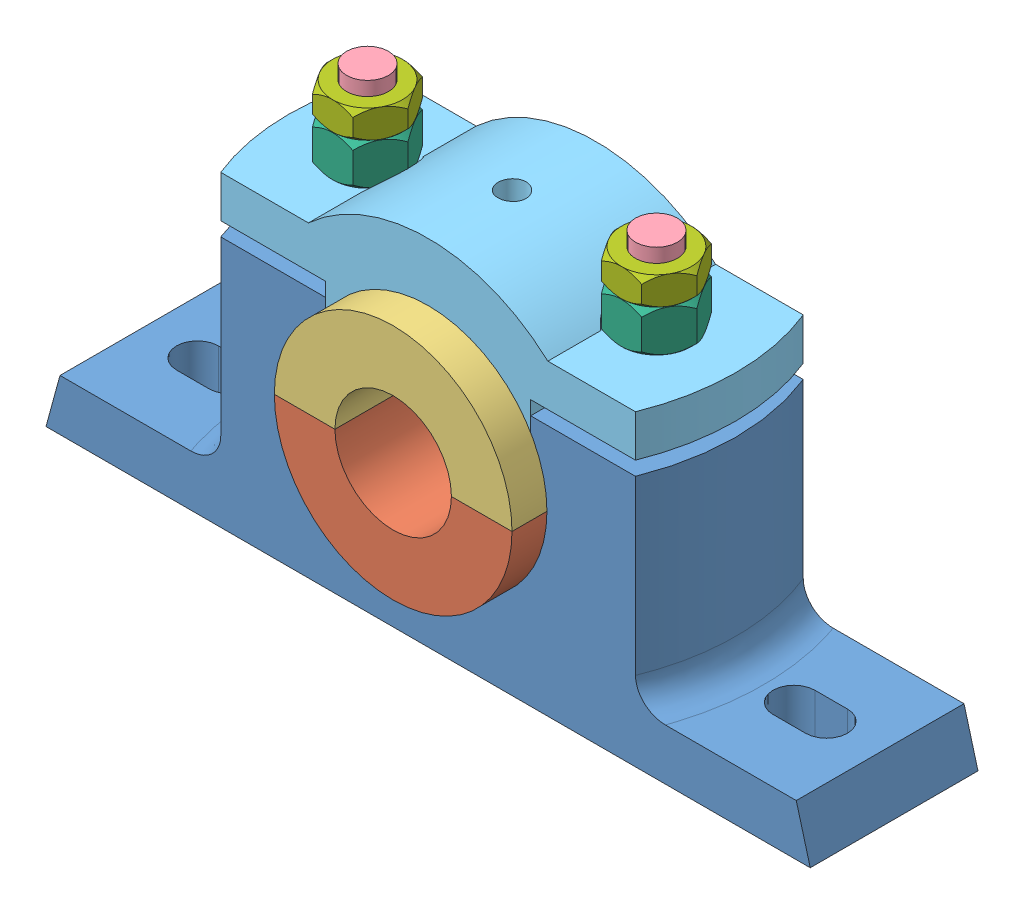
SolidWorks assembly assembly1, configuration Default. Lengths in mm.
Overall size (164 84 51).
10 component instances, 7 part files, 20 mates.
Components (placement in the parent):
- casting-1: casting [Default] at (63.4243 37.0693 139.336) size (164 54 36)
- lower brass-1: lower brass [Default] at (63.4243 75.0693 139.336) size (51 25.5 51)
- upper brass-1: upper brass [Default] at (63.4243 75.0693 139.336) size (51 25.5 51)
- bolt-1: bolt [Default] at (23.2034 39.0693 148.836) size (19 82 19)
- cap-1: cap [Default] at (63.4243 75.0693 139.336) size (96 32 36)
- bolt-2: bolt [Default] at (85.2034 39.0693 148.836) size (19 82 19)
- NUT 9mm thick-1: NUT 9mm thick [Default] at (94.4243 107.5693 139.336) x (1 0 0) z (0 -1 0) size (19.05 15 9)
- nut 6mm thick-3: nut 6mm thick [Default] at (94.4243 115.0693 139.336) x (1 0 0) z (0 -1 0) size (19.05 15 6)
- NUT 9mm thick-2: NUT 9mm thick [Default] at (32.4243 107.5693 139.336) x (1 0 0) z (0 -1 0) size (19.05 15 9)
- nut 6mm thick-4: nut 6mm thick [Default] at (32.4243 115.0693 139.336) x (1 0 0) z (0 1 0) size (19.05 15 6)
Mates (geometry in assembly coordinates):
- Concentric1: concentric aligned: cylinder of casting-1 through (63.4243 75.0693 157.336) axis (0 0 -1) radius 19; cylinder of lower brass-1 through (63.4243 75.0693 139.336) axis (0 0 -1) radius 12.5
- Coincident1: coincident anti-aligned: cylinder of casting-1 through (63.4243 56.0693 139.336) axis (0 1 0) radius 3; circle of lower brass-1
- Concentric2: concentric anti-aligned: cylinder of lower brass-1 through (63.4243 75.0693 139.336) axis (0 0 -1) radius 12.5; cylinder of upper brass-1 through (63.4243 75.0693 139.336) axis (0 0 1) radius 12.5
- Coincident2: coincident anti-aligned: plane of lower brass-1 through (63.4243 75.0693 139.336) normal (0 1 0); plane of upper brass-1 through (63.4243 75.0693 139.336) normal (0 -1 0)
- Coincident5: coincident aligned: plane of lower brass-1 through (75.9243 75.0693 113.836) normal (0 0 -1); plane of upper brass-1 through (75.9243 75.0693 113.836) normal (0 0 -1)
- Parallel6: parallel anti-aligned: plane of casting-1 through (22.4243 45.0693 129.336) normal (1 0 0); plane of bolt-1 through (23.2034 45.0693 148.836) normal (-1 0 0)
- Concentric3: concentric aligned: cylinder of casting-1 through (32.4243 37.0693 139.336) axis (0 1 0) radius 4.5; cylinder of cap-1 through (32.4243 45.0693 139.336) axis (0 1 0) radius 4.5
- Concentric6: concentric anti-aligned: cylinder of casting-1 through (32.4243 37.0693 139.336) axis (0 1 0) radius 4.5; cylinder of bolt-1 through (32.4243 121.0693 139.336) axis (0 -1 0) radius 4.5
- Coincident28: coincident anti-aligned: plane of casting-1 through (63.4243 45.0693 139.336) normal (0 -1 0); plane of bolt-1 through (23.2034 45.0693 148.836) normal (0 1 0)
- Concentric10: concentric anti-aligned: cylinder of upper brass-1 through (63.4243 75.0693 139.336) axis (0 0 1) radius 17.5; cylinder of cap-1 through (63.4243 75.0693 157.336) axis (0 0 -1) radius 19
- Concentric15: concentric anti-aligned: cylinder of casting-1 through (94.4243 37.0693 139.336) axis (0 1 0) radius 4.5; cylinder of bolt-2 through (94.4243 121.0693 139.336) axis (0 -1 0) radius 4.5
- Coincident34: coincident anti-aligned: plane of casting-1 through (63.4243 45.0693 139.336) normal (0 -1 0); plane of bolt-2 through (85.2034 45.0693 148.836) normal (0 1 0)
- Concentric17: concentric anti-aligned: cylinder of bolt-2 through (94.4243 121.0693 139.336) axis (0 -1 0) radius 4.5; cylinder of NUT 9mm thick-1 through (94.4243 103.0693 139.336) axis (0 1 0) radius 4.5
- Coincident36: coincident anti-aligned: plane of cap-1 through (113.4243 103.0693 157.336) normal (0 1 0); plane of NUT 9mm thick-1 through (94.4243 103.0693 139.336) normal (0 -1 0)
- Concentric18: concentric anti-aligned: cylinder of bolt-2 through (94.4243 121.0693 139.336) axis (0 -1 0) radius 4.5; cylinder of nut 6mm thick-3 through (94.4243 112.0693 139.336) axis (0 1 0) radius 4.5
- Coincident37: coincident anti-aligned: plane of NUT 9mm thick-1 through (94.4243 112.0693 139.336) normal (0 1 0); plane of nut 6mm thick-3 through (94.4243 112.0693 139.336) normal (0 -1 0)
- Concentric19: concentric anti-aligned: cylinder of bolt-1 through (32.4243 121.0693 139.336) axis (0 -1 0) radius 4.5; cylinder of NUT 9mm thick-2 through (32.4243 103.0693 139.336) axis (0 1 0) radius 4.5
- Coincident38: coincident anti-aligned: plane of cap-1 through (13.4243 103.0693 157.336) normal (0 1 0); plane of NUT 9mm thick-2 through (32.4243 103.0693 139.336) normal (0 -1 0)
- Coincident39: coincident anti-aligned: plane of NUT 9mm thick-2 through (32.4243 112.0693 139.336) normal (0 1 0); plane of nut 6mm thick-4 through (32.4243 112.0693 139.336) normal (0 -1 0)
- Concentric22: concentric aligned: cylinder of bolt-1 through (32.4243 121.0693 139.336) axis (0 -1 0) radius 4.5; cylinder of nut 6mm thick-4 through (32.4243 118.0693 139.336) axis (0 -1 0) radius 4.5
